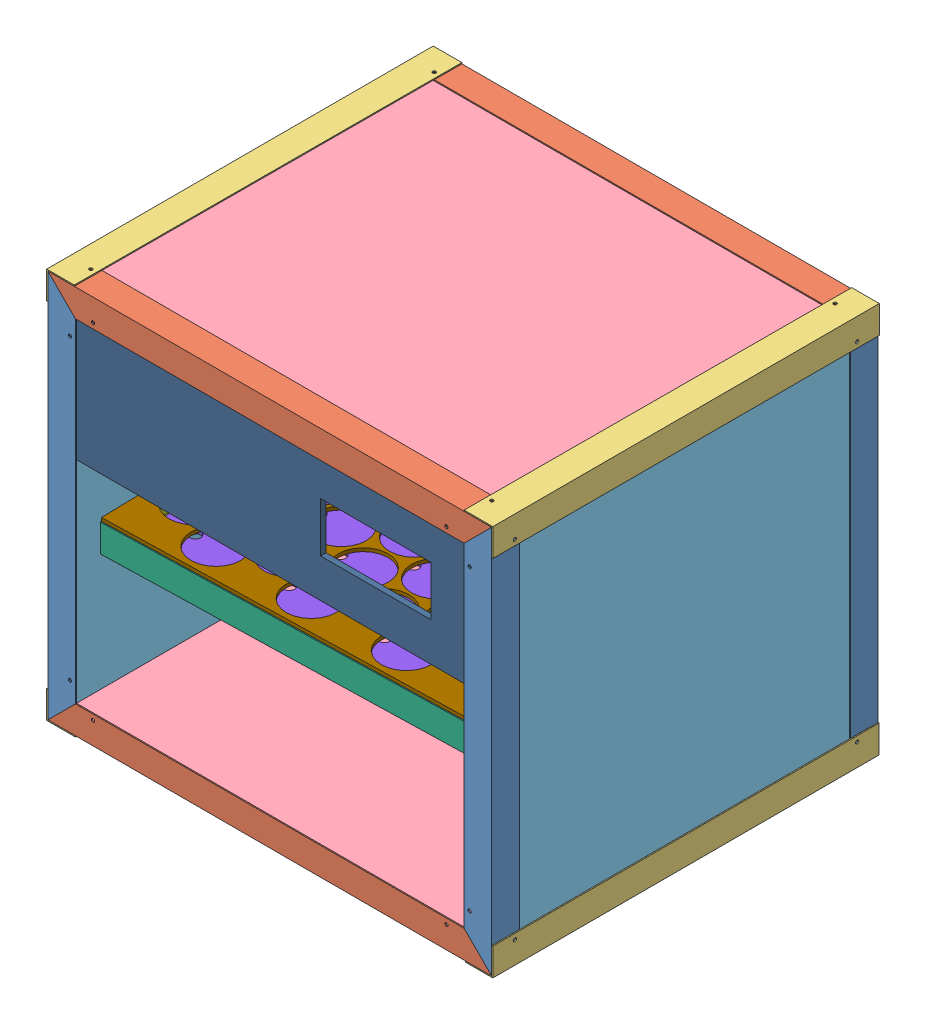
SolidWorks assembly INCUBADORA3.0, configuration Predeterminado. Lengths in mm.
Overall size (404 354 350).
25 component instances, 10 part files, 46 mates.
Components (placement in the parent):
- Soporte_Estructura_vertica_35x2.5x0.1-2: Soporte_Estructura_vertica_35x2.5x0.1 [Predeterminado] at (-274.9823 81.7283 362.5001) x (-1 0 0) z (0 0 -1) size (25 350 25)
- Soporte_Estructura_Horizontal_40x2.5x0.1-1: Soporte_Estructura_Horizontal_40x2.5x0.1 [Predeterminado] at (73.2791 198.3504 362.5001) x (0 1 0) z (0 0 -1) size (25 400 25)
- Soporte_Estructura_Horizontal_40x2.5x0.1-2: Soporte_Estructura_Horizontal_40x2.5x0.1 [Predeterminado] at (-112.3602 -262.5331 362.5001) x (0 -1 0) z (0 0 -1) size (25 400 25)
- Soporte_Estructura_vertica_35x2.5x0.1-3: Soporte_Estructura_vertica_35x2.5x0.1 [Predeterminado] at (235.9013 -145.911 362.5001) x (1 0 0) z (0 0 -1) size (25 350 25)
- Soporte_Estructura_Esquinas_35x2.5x0.1-1: Soporte_Estructura_Esquinas_35x2.5x0.1 [Predeterminado] at (236.9013 144.9086 301.3197) x (1 0 0) z (0 -1 0) size (26 350 25)
- Soporte_Estructura_Esquinas_35x2.5x0.1-2: Soporte_Estructura_Esquinas_35x2.5x0.1 [Predeterminado] at (-275.9633 144.9086 73.6768) x (-1 0 -0.000066) z (0 -1 0) size (26 350 25)
- Soporte_Estructura_Esquinas_35x2.5x0.1-3: Soporte_Estructura_Esquinas_35x2.5x0.1 [Predeterminado] at (-275.9823 -209.0914 301.3197) x (-1 0 0) z (0 1 0) size (26 350 25)
- Soporte_Estructura_Esquinas_35x2.5x0.1-4: Soporte_Estructura_Esquinas_35x2.5x0.1 [Predeterminado] at (236.8823 -209.0914 73.6768) x (1 0 -0.000066) z (0 1 0) size (26 350 25)
- Soporte_Estructura_Horizontal_40x2.5x0.1-3: Soporte_Estructura_Horizontal_40x2.5x0.1 [Predeterminado] at (-112.3371 198.3504 12.5072) x (0 1 0) z (-0.000066 0 1) size (25 400 25)
- Soporte_Estructura_vertica_35x2.5x0.1-4: Soporte_Estructura_vertica_35x2.5x0.1 [Predeterminado] at (235.9243 81.7283 12.5301) x (1 0 0.000066) z (-0.000066 0 1) size (25 350 25)
- Soporte_Estructura_Horizontal_40x2.5x0.1-4: Soporte_Estructura_Horizontal_40x2.5x0.1 [Predeterminado] at (73.3021 -262.5331 12.5194) x (0 -1 0) z (-0.000066 0 1) size (25 400 25)
- Soporte_Estructura_vertica_35x2.5x0.1-5: Soporte_Estructura_vertica_35x2.5x0.1 [Predeterminado] at (-274.9593 -145.911 12.4965) x (-1 0 -0.000066) z (-0.000066 0 1) size (25 350 25)
- PVC_34x39x0.5-1: PVC_34x39x0.5 [Predeterminado] at (125.9421 137.9086 79.5757) x (-0.000066 0 1) z (0 1 0) size (340 390 5)
- PVC_34x39x0.5-2: PVC_34x39x0.5 [Predeterminado] at (125.9464 76.8558 13.5229) x (0 -1 0) z (-0.000066 0 1) size (340 390 5)
- PVC_34x34x0.5-1: PVC_34x34x0.5 [Predeterminado] at (-214.5219 88.3726 79.5533) x (-0.000066 0 1) z (-1 0 -0.000066) size (340 340 5)
- PVC_34x34x0.5-2: PVC_34x34x0.5 [Predeterminado] at (175.4638 88.3726 297.4733) x (0.000066 0 -1) z (1 0 0.000066) size (340 340 5)
- PVC_34x39x0.5-3: PVC_34x39x0.5 [Predeterminado] at (125.9421 -207.0914 79.5757) x (-0.000066 0 1) z (0 1 0) size (340 390 5)
- Bandeja_Huevos_27x36x2.5-1: Bandeja_Huevos_27x36x2.5 [Predeterminado] at (-24.164 -471.3198 303.532) x (0.026096 0.002054 0.999657) z (-0.000027 0.999998 -0.002054) size (272 362 29)
  - Soporte_Bandeja_Horizonta_40x2.5x0.1-1: Soporte_Bandeja_Horizonta_40x2.5x0.1 [Predeterminado] at (53.9361 154.3977 387.5) size (25 360 25)
  - Soporte_Bandeja_Horizonta_40x2.5x0.1-4: Soporte_Bandeja_Horizonta_40x2.5x0.1 [Predeterminado] at (-274.8673 -152.6319 387.5) x (-1 0 0) z (0 0 1) size (25 360 25)
  - Soporte_Bandeja_Vertical_27x2.5x0.1-2: Soporte_Bandeja_Vertical_27x2.5x0.1 [Predeterminado] at (-218.9804 210.2846 386.5) x (0 1 0) z (0 0 1) size (25 270 25)
  - Soporte_Bandeja_Vertical_27x2.5x0.1-3: Soporte_Bandeja_Vertical_27x2.5x0.1 [Predeterminado] at (-1.9508 -208.5189 386.5) x (0 -1 0) z (0 0 1) size (25 270 25)
  - Bandeja_Down_27x36x0.5-1: Bandeja_Down_27x36x0.5 [Predeterminado] at (-199.9841 -101.0844 388.5) x (0 1 0) z (0 0 1) size (350 260 3)
  - Bandeja_Up_27x36x0.3-1: Bandeja_Up_27x36x0.3 [Predeterminado] at (-20.9471 102.8502 412.5) x (0 -1 0) z (0 0 1) size (360 270 3)
- PVC_15x39x0.5-1: PVC_15x39x0.5 [Predeterminado] at (110.8382 76.8558 356.5001) x (0 -1 0) z (0 0 1) size (130 390 5)
Mates (geometry in assembly coordinates):
- Coincidente1: coincident aligned: line of Soporte_Estructura_Horizontal_40x2.5x0.1-1 through (180.4595 142.9086 337.5001) axis (0 0 1); line of Soporte_Estructura_vertica_35x2.5x0.1-3 through (180.4595 142.9086 337.5001) axis (0 0 1)
- Coincidente2: coincident aligned: line of Soporte_Estructura_vertica_35x2.5x0.1-2 through (-219.5405 142.9086 337.5001) axis (0 0 1); line of Soporte_Estructura_Horizontal_40x2.5x0.1-1 through (-219.5405 142.9086 337.5001) axis (0 0 1)
- Coincidente3: coincident aligned: line of Soporte_Estructura_Horizontal_40x2.5x0.1-2 through (180.4595 -207.0914 337.5001) axis (0 0 1); line of Soporte_Estructura_vertica_35x2.5x0.1-3 through (180.4595 -207.0914 337.5001) axis (0 0 1)
- Coincidente4: coincident aligned: line of Soporte_Estructura_vertica_35x2.5x0.1-2 through (-219.5405 -207.0914 337.5001) axis (0 0 1); line of Soporte_Estructura_Horizontal_40x2.5x0.1-2 through (-219.5405 -207.0914 337.5001) axis (0 0 1)
- Coincidente5: coincident aligned: plane of Soporte_Estructura_vertica_35x2.5x0.1-2 through (-274.9823 81.7283 362.5001) normal (0 0 1); plane of Soporte_Estructura_Horizontal_40x2.5x0.1-2 through (-112.3602 -262.5331 362.5001) normal (0 0 1)
- Coincidente7: coincident aligned: plane of Soporte_Estructura_vertica_35x2.5x0.1-2 through (-274.9823 81.7283 362.5001) normal (0 0 1); plane of Soporte_Estructura_Horizontal_40x2.5x0.1-1 through (73.2791 198.3504 362.5001) normal (0 0 1)
- Coincidente8: coincident aligned: plane of Soporte_Estructura_Horizontal_40x2.5x0.1-1 through (73.2791 198.3504 362.5001) normal (0 0 1); plane of Soporte_Estructura_vertica_35x2.5x0.1-3 through (235.9013 -145.911 362.5001) normal (0 0 1)
- Coincidente9: coincident aligned: line of Soporte_Estructura_vertica_35x2.5x0.1-2 through (-195.5405 -183.0914 361.5001) axis (0 0 1); line of Soporte_Estructura_Horizontal_40x2.5x0.1-2 through (-195.5405 -183.0914 361.5001) axis (0 0 1)
- Coincidente10: coincident anti-aligned: plane of Soporte_Estructura_vertica_35x2.5x0.1-3 through (181.4595 -207.0914 337.5001) normal (1 0 0); plane of Soporte_Estructura_Esquinas_35x2.5x0.1-1 through (181.4595 119.9086 362.5001) normal (-1 0 0)
- Coincidente11: coincident anti-aligned: plane of Soporte_Estructura_Horizontal_40x2.5x0.1-1 through (180.4595 143.9086 337.5001) normal (0 1 0); plane of Soporte_Estructura_Esquinas_35x2.5x0.1-1 through (236.9013 143.9086 301.3197) normal (0 -1 0)
- Coincidente12: coincident aligned: plane of Soporte_Estructura_vertica_35x2.5x0.1-3 through (235.9013 -145.911 362.5001) normal (0 0 1); plane of Soporte_Estructura_Esquinas_35x2.5x0.1-1 through (181.4595 119.9086 362.5001) normal (0 0 1)
- Coincidente20: coincident anti-aligned: line of Soporte_Estructura_Horizontal_40x2.5x0.1-1 through (-219.5405 143.9086 362.5001) axis (1 0 0); line of Soporte_Estructura_Esquinas_35x2.5x0.1-2 through (-196.5906 143.9086 362.5001) axis (-1 0 0)
- Coincidente23: coincident aligned: line of Soporte_Estructura_vertica_35x2.5x0.1-2 through (-220.5405 -207.0914 362.5001) axis (0 1 0); line of Soporte_Estructura_Esquinas_35x2.5x0.1-2 through (-220.5405 119.9086 362.5001) axis (0 1 0)
- Coincidente24: coincident anti-aligned: line of Soporte_Estructura_Horizontal_40x2.5x0.1-2 through (180.4595 -208.0914 362.5001) axis (-1 0 0); line of Soporte_Estructura_Esquinas_35x2.5x0.1-4 through (157.5095 -208.0914 362.5001) axis (1 0 0)
- Coincidente25: coincident aligned: line of Soporte_Estructura_vertica_35x2.5x0.1-3 through (181.4595 142.9086 362.5001) axis (0 -1 0); line of Soporte_Estructura_Esquinas_35x2.5x0.1-4 through (181.4595 -184.0914 362.5001) axis (0 -1 0)
- Coincidente26: coincident anti-aligned: line of Soporte_Estructura_Horizontal_40x2.5x0.1-2 through (180.4595 -208.0914 362.5001) axis (-1 0 0); line of Soporte_Estructura_Esquinas_35x2.5x0.1-3 through (-220.5405 -208.0914 362.5001) axis (1 0 0)
- Coincidente27: coincident anti-aligned: line of Soporte_Estructura_vertica_35x2.5x0.1-2 through (-220.5405 -207.0914 362.5001) axis (0 1 0); line of Soporte_Estructura_Esquinas_35x2.5x0.1-3 through (-220.5405 -184.0914 362.5001) axis (0 -1 0)
- Coincidente28: coincident aligned: plane of Soporte_Estructura_Esquinas_35x2.5x0.1-2 through (-220.5175 119.9086 12.5001) normal (0.000066 0 -1); plane of Soporte_Estructura_Horizontal_40x2.5x0.1-3 through (-112.3371 198.3504 12.5072) normal (0.000066 0 -1)
- Coincidente29: coincident anti-aligned: plane of Soporte_Estructura_Esquinas_35x2.5x0.1-2 through (-275.9633 143.9086 73.6768) normal (0 -1 0); plane of Soporte_Estructura_Horizontal_40x2.5x0.1-3 through (-219.5192 143.9086 37.5002) normal (0 1 0)
- Coincidente30: coincident aligned: line of Soporte_Estructura_Horizontal_40x2.5x0.1-3 through (156.4824 118.9086 13.5249) axis (0.000066 0 -1); line of Soporte_Estructura_vertica_35x2.5x0.1-4 through (156.4824 118.9086 13.5249) axis (0.000066 0 -1)
- Coincidente31: coincident aligned: line of Soporte_Estructura_Horizontal_40x2.5x0.1-3 through (180.4808 142.9086 37.5265) axis (0.000066 0 -1); line of Soporte_Estructura_vertica_35x2.5x0.1-4 through (180.4808 142.9086 37.5265) axis (0.000066 0 -1)
- Coincidente32: coincident aligned: plane of Soporte_Estructura_Horizontal_40x2.5x0.1-3 through (-112.3371 198.3504 12.5072) normal (0.000066 0 -1); plane of Soporte_Estructura_vertica_35x2.5x0.1-4 through (235.9243 81.7283 12.5301) normal (0.000066 0 -1)
- Coincidente34: coincident anti-aligned: plane of Soporte_Estructura_Esquinas_35x2.5x0.1-4 through (236.8823 -208.0914 73.6768) normal (0 1 0); plane of Soporte_Estructura_Horizontal_40x2.5x0.1-4 through (180.4808 -208.0914 37.5265) normal (0 -1 0)
- Coincidente35: coincident aligned: line of Soporte_Estructura_vertica_35x2.5x0.1-4 through (180.4808 -207.0914 37.5265) axis (0.000066 0 -1); line of Soporte_Estructura_Horizontal_40x2.5x0.1-4 through (180.4808 -207.0914 37.5265) axis (0.000066 0 -1)
- Coincidente36: coincident aligned: plane of Soporte_Estructura_vertica_35x2.5x0.1-4 through (235.9243 81.7283 12.5301) normal (0.000066 0 -1); plane of Soporte_Estructura_Horizontal_40x2.5x0.1-4 through (73.3021 -262.5331 12.5194) normal (0.000066 0 -1)
- Coincidente37: coincident anti-aligned: plane of Soporte_Estructura_Esquinas_35x2.5x0.1-2 through (-220.5175 119.9086 12.5001) normal (1 0 0.000066); plane of Soporte_Estructura_vertica_35x2.5x0.1-5 through (-220.5192 -207.0914 37.5001) normal (-1 0 -0.000066)
- Coincidente38: coincident aligned: line of Soporte_Estructura_Horizontal_40x2.5x0.1-3 through (-219.5192 142.9086 37.5002) axis (0.000066 0 -1); line of Soporte_Estructura_vertica_35x2.5x0.1-5 through (-219.5192 142.9086 37.5002) axis (0.000066 0 -1)
- Coincidente39: coincident aligned: plane of Soporte_Estructura_Horizontal_40x2.5x0.1-3 through (-112.3371 198.3504 12.5072) normal (0.000066 0 -1); plane of Soporte_Estructura_vertica_35x2.5x0.1-5 through (-274.9593 -145.911 12.4965) normal (0.000066 0 -1)
- Coincidente43: coincident anti-aligned: plane of Soporte_Estructura_Horizontal_40x2.5x0.1-3 through (-219.5192 142.9086 37.5002) normal (0 -1 0); plane of PVC_34x39x0.5-1 through (125.9421 142.9086 79.5757) normal (0 1 0)
- Distancia3: distance = 5 mm anti-aligned: plane of PVC_34x39x0.5-1 through (175.4821 142.9086 18.5261) normal (0.000066 0 -1); plane of Soporte_Estructura_Horizontal_40x2.5x0.1-3 through (-112.3372 198.3504 13.5072) normal (-0.000066 0 1)
- Distancia4: distance = 5 mm anti-aligned: plane of Soporte_Estructura_vertica_35x2.5x0.1-4 through (180.4808 142.9086 37.5265) normal (-1 0 -0.000066); plane of PVC_34x39x0.5-1 through (175.4821 142.9086 18.5261) normal (1 0 0.000066)
- Distancia6: distance = 5 mm anti-aligned: plane of PVC_34x39x0.5-2 through (175.4821 -202.0914 18.5261) normal (0 -1 0); plane of Soporte_Estructura_Horizontal_40x2.5x0.1-4 through (180.4808 -207.0914 37.5265) normal (0 1 0)
- Distancia7: distance = 5 mm anti-aligned: plane of PVC_34x39x0.5-2 through (-214.5179 137.9086 18.5005) normal (-1 0 -0.000066); plane of Soporte_Estructura_vertica_35x2.5x0.1-5 through (-219.5192 -207.0914 37.5002) normal (1 0 0.000066)
- Coincidente51: coincident anti-aligned: plane of Soporte_Estructura_vertica_35x2.5x0.1-5 through (-274.9594 -145.911 13.4965) normal (-0.000066 0 1); plane of PVC_34x39x0.5-2 through (125.9464 76.8558 13.5229) normal (0.000066 0 -1)
- Distancia8: distance = 5 mm anti-aligned: plane of PVC_34x34x0.5-1 through (-219.5179 137.9086 18.5002) normal (0 1 0); plane of Soporte_Estructura_Horizontal_40x2.5x0.1-3 through (-219.5192 142.9086 37.5002) normal (0 -1 0)
- Distancia9: distance = 5 mm anti-aligned: plane of PVC_34x34x0.5-1 through (-219.5179 137.9086 18.5002) normal (0.000066 0 -1); plane of Soporte_Estructura_vertica_35x2.5x0.1-5 through (-274.9594 -145.911 13.4965) normal (-0.000066 0 1)
- Coincidente56: coincident anti-aligned: plane of Soporte_Estructura_vertica_35x2.5x0.1-5 through (-219.5192 -207.0914 37.5002) normal (1 0 0.000066); plane of PVC_34x34x0.5-1 through (-219.5219 88.3726 79.553) normal (-1 0 -0.000066)
- Coincidente57: coincident anti-aligned: plane of Soporte_Estructura_vertica_35x2.5x0.1-4 through (180.4808 142.9086 37.5265) normal (-1 0 -0.000066); plane of PVC_34x34x0.5-2 through (180.4638 88.3726 297.4737) normal (1 0 0.000066)
- Distancia10: distance = 5 mm anti-aligned: plane of Soporte_Estructura_vertica_35x2.5x0.1-4 through (235.9242 81.7283 13.5301) normal (-0.000066 0 1); plane of PVC_34x34x0.5-2 through (180.4821 137.9086 18.5265) normal (0.000066 0 -1)
- Distancia11: distance = 5 mm anti-aligned: plane of Soporte_Estructura_Horizontal_40x2.5x0.1-4 through (180.4808 -207.0914 37.5265) normal (0 1 0); plane of PVC_34x34x0.5-2 through (180.4597 -202.0914 358.5265) normal (0 -1 0)
- Distancia14: distance = 5 mm anti-aligned: plane of Soporte_Estructura_Horizontal_40x2.5x0.1-4 through (73.3021 -262.5331 13.5194) normal (-0.000066 0 1); plane of PVC_34x39x0.5-3 through (175.4821 -202.0914 18.5261) normal (0.000066 0 -1)
- Distancia15: distance = 5 mm anti-aligned: plane of Soporte_Estructura_vertica_35x2.5x0.1-4 through (180.4808 142.9086 37.5265) normal (-1 0 -0.000066); plane of PVC_34x39x0.5-3 through (175.4821 -202.0914 18.5261) normal (1 0 0.000066)
- Coincidente67: coincident anti-aligned: plane of Soporte_Estructura_Horizontal_40x2.5x0.1-4 through (180.4808 -207.0914 37.5265) normal (0 1 0); plane of PVC_34x39x0.5-3 through (125.9421 -207.0914 79.5757) normal (0 -1 0)
- Distancia17: distance = 5 mm anti-aligned: plane of Soporte_Estructura_Horizontal_40x2.5x0.1-1 through (180.4595 142.9086 337.5001) normal (0 -1 0); plane of PVC_15x39x0.5-1 through (175.4595 137.9086 361.5001) normal (0 1 0)
- Distancia16: distance = 5 mm anti-aligned: plane of Soporte_Estructura_vertica_35x2.5x0.1-3 through (180.4595 -207.0914 337.5001) normal (-1 0 0); plane of PVC_15x39x0.5-1 through (175.4595 137.9086 361.5001) normal (1 0 0)
- Coincidente70: coincident anti-aligned: plane of Soporte_Estructura_vertica_35x2.5x0.1-2 through (-274.9823 81.7283 361.5001) normal (0 0 -1); plane of PVC_15x39x0.5-1 through (110.8382 76.8558 361.5001) normal (0 0 1)
